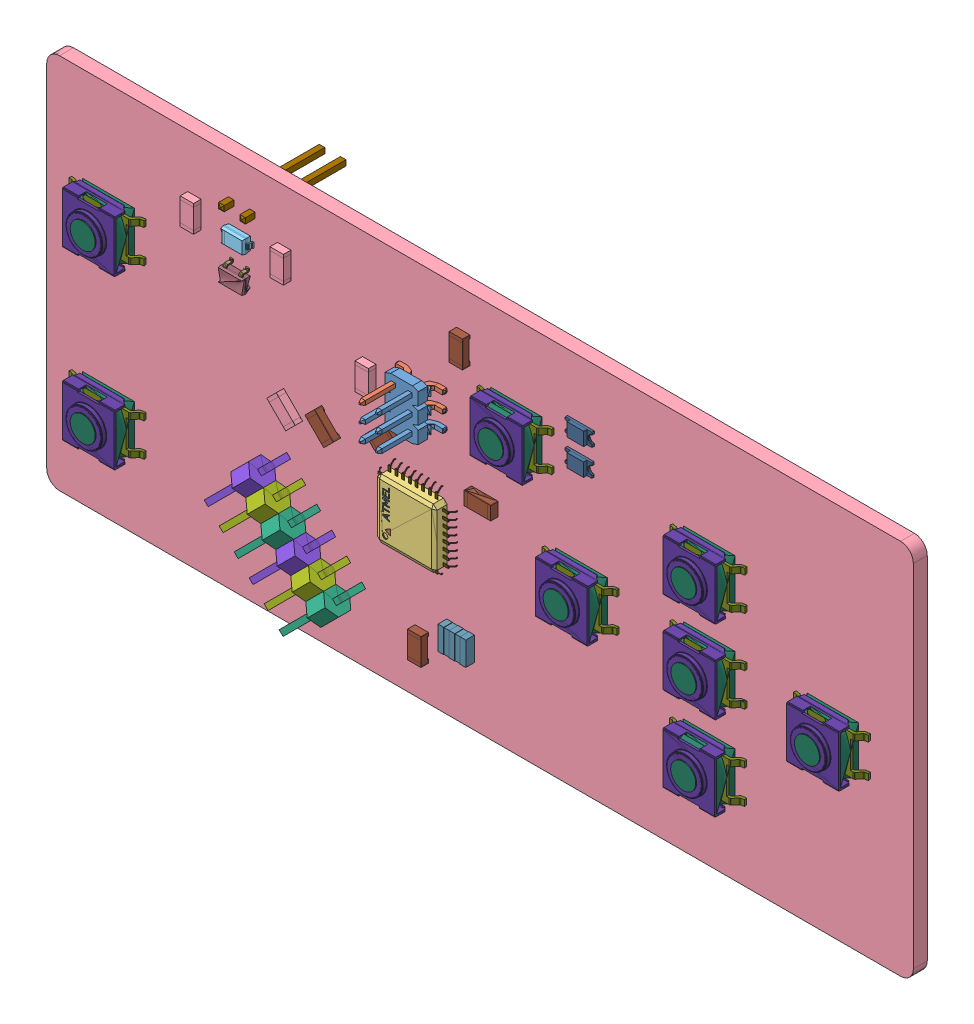
SolidWorks assembly model3, configuration Default. Lengths in mm.
Overall size (103.07 45.07 17.73).
109 component instances, 25 part files, 0 mates.
Components (placement in the parent):
- 2X03SMD-1: 2X03SMD [Default] at (2993.2271 13531.488 -10410.0341) x (-1 0 0) z (0 0 1) size (5.95 6.45 6.6)
  - skpxI6tRR-1: skpxI6tRR [Default] x (0 -1 0) z (0 0 1) size (5.95 5.95 6.6)
    - skpxI6tRR-1-1: skpxI6tRR-1 [Default] at origin size (5.95 4.96 6.6)
    - skpxI6tRR-2-1: skpxI6tRR-2 [Default] at origin size (2.53 5.95 6.6)
    - skpxI6tRR-3-1: skpxI6tRR-3 [Default] at origin size (0.5 2.23 1.49)
  - skpxI6tRR-2: skpxI6tRR [Default] x (0 -1 0) z (0 0 1) size (6.45 5.95 6.55)
- C1206-1: C1206 [Default] at (2986.7985 13530.1039 -10412.8609) x (0 -1 0) z (0 0 1) size (3.18 1.59 0.89)
- C1206-2: C1206 [Default] at (2977.1959 13522.0391 -10412.8609) x (-0.707107 0.707107 0) z (0 0 1) size (3.18 1.59 0.89)
- C1206-3: C1206 [Default] at (2976.6918 13536.8083 -10412.8609) x (0 1 0) z (0 0 1) size (3.18 1.59 0.89)
- C1206-4: C1206 [Default] at (2966.0066 13536.7071 -10412.8609) x (0 -1 0) z (0 0 1) size (3.18 1.59 0.89)
- SOD123-1: SOD123 [Default] at (2971.3993 13536.7071 -10412.8113) size (3.39 1.59 0.99)
- 1X06SMD-1: 1X06SMD [Default] at (2977.8455 13508.7982 -10412.2713) x (-0.707107 -0.707107 0) z (0 0 1) size (10.7 15.51 4.98)
  - PIN_HEADER_L-ANGLE-1: PIN_HEADER_L-ANGLE [Default] at (0 3.7803 0) x (0 0 -1) z (1 0 0) size (4.98 7.95 10.7)
    - Group_28-1: Group_28 [Default] at (0.0033 2.5199 0) size (4.97 2.91 10.7)
    - Group_25-1: Group_25 [Default] at origin size (4.97 2.91 10.7)
    - Group_29-1: Group_29 [Default] at (-0.0033 -2.5199 0) size (4.97 2.91 10.7)
  - PIN_HEADER_L-ANGLE-2: PIN_HEADER_L-ANGLE [Default] at (0 -3.7803 0) x (0 0 -1) z (1 0 0) size (4.98 7.95 10.7)
    - Group_28-1: Group_28 [Default] at (0.0033 2.5199 0) size (4.97 2.91 10.7)
    - Group_25-1: Group_25 [Default] at origin size (4.97 2.91 10.7)
    - Group_29-1: Group_29 [Default] at (-0.0033 -2.5199 0) size (4.97 2.91 10.7)
- 1X2-1: 1X2 [Default] at (2971.5868 13539.7476 -10418.2528) x (1 0 0) z (0 0 -1) size (5.25 2.82 12.38)
  - Componente_1-1: Componente_1 [Default] at origin size (5.25 2.82 12.38)
    - Pin-1: Pin [Default] at (1.2601 0 0) x (0 1 0) z (0 0 1) size (2.82 2.73 12.38)
    - Pin-2: Pin [Default] at (-1.2601 0 0) x (0 1 0) z (0 0 1) size (2.82 2.73 12.38)
- LED_1206-1: LED_1206 [Default] at (3011.9764 13533.8473 -10412.97) x (-1 0 0) z (0 0 1) size (3.18 1.59 0.67)
- LED_1206-2: LED_1206 [Default] at (3011.9818 13537.0252 -10412.97) size (3.18 1.59 0.67)
- R1206-1: R1206 [Default] at (3000.5586 13524.0553 -10412.8609) size (3.18 1.59 0.89)
- R1206-2: R1206 [Default] at (2997.9878 13538.7233 -10412.8609) x (0 1 0) z (0 0 1) size (3.18 1.59 0.89)
- R1206-3: R1206 [Default] at (2988.8901 13525.3154 -10412.8609) x (-0.707107 -0.707107 0) z (0 0 1) size (3.18 1.59 0.89)
- R1206-4: R1206 [Default] at (2993.0485 13505.608 -10412.8609) x (0 1 0) z (0 0 1) size (3.18 1.59 0.89)
- R1206-5: R1206 [Default] at (2981.7323 13522.569 -10412.8609) x (-0.707107 0.707107 0) z (0 0 1) size (3.18 1.59 0.89)
- SOT23-1: SOT23 [Default] at (2971.4251 13532.7253 -10412.7121) x (-1 0 0) z (0 0 1) size (2.88 2.68 1.19)
  - Groupe_1-1: Groupe_1 [Default] at (-0.9426 -1.0666 -0.1488) size (0.66 0.55 0.89)
  - Groupe_1-2: Groupe_1 [Default] at (0.9426 -1.0666 -0.1488) size (0.66 0.55 0.89)
  - Groupe_1-3: Groupe_1 [Default] at (0 1.0666 -0.1488) x (-1 0 0) z (0 0 1) size (0.66 0.55 0.89)
  - SOT23-1: SOT23 [Default] at origin size (2.88 1.59 1.19)
- EFOBM-1: EFOBM [Default] at (2998.2004 13508.7789 -10412.2645) x (0 -1 0) z (0 0 1) size (2.83 3.3 1.04)
- 6MM_SWITCH-1: 6MM_SWITCH [Default] at (3004.2884 13533.3306 -10411.8044) x (-1 0 0) z (0 0 1) size (8.92 6.58 3.14)
  - _1-1: _1 [Default] at (0 0 0.0343) size (6.15 6.15 3.07)
  - _2-1: _2 [Default] at (0 0 -1.0585) size (8.92 4.66 1.03)
  - _3-1: _3 [Default] at (0 0 0.3116) size (6.16 6.58 2.49)
- 6MM_SWITCH-2: 6MM_SWITCH [Default] at (2955.7997 13510.6733 -10411.8044) size (8.92 6.58 3.14)
  - _1-1: _1 [Default] at (0 0 0.0343) size (6.15 6.15 3.07)
  - _2-1: _2 [Default] at (0 0 -1.0585) size (8.92 4.66 1.03)
  - _3-1: _3 [Default] at (0 0 0.3116) size (6.16 6.58 2.49)
- 6MM_SWITCH-3: 6MM_SWITCH [Default] at (3027.2225 13510.6227 -10411.8044) x (-1 0 0) z (0 0 1) size (8.92 6.58 3.14)
  - _1-1: _1 [Default] at (0 0 0.0343) size (6.15 6.15 3.07)
  - _2-1: _2 [Default] at (0 0 -1.0585) size (8.92 4.66 1.03)
  - _3-1: _3 [Default] at (0 0 0.3116) size (6.16 6.58 2.49)
- 6MM_SWITCH-4: 6MM_SWITCH [Default] at (3012.0505 13520.653 -10411.8044) size (8.92 6.58 3.14)
  - _1-1: _1 [Default] at (0 0 0.0343) size (6.15 6.15 3.07)
  - _2-1: _2 [Default] at (0 0 -1.0585) size (8.92 4.66 1.03)
  - _3-1: _3 [Default] at (0 0 0.3116) size (6.16 6.58 2.49)
- 6MM_SWITCH-5: 6MM_SWITCH [Default] at (3027.2483 13520.653 -10411.8044) size (8.92 6.58 3.14)
  - _1-1: _1 [Default] at (0 0 0.0343) size (6.15 6.15 3.07)
  - _2-1: _2 [Default] at (0 0 -1.0585) size (8.92 4.66 1.03)
  - _3-1: _3 [Default] at (0 0 0.3116) size (6.16 6.58 2.49)
- 6MM_SWITCH-6: 6MM_SWITCH [Default] at (2955.7997 13530.5831 -10411.8044) size (8.92 6.58 3.14)
  - _1-1: _1 [Default] at (0 0 0.0343) size (6.15 6.15 3.07)
  - _2-1: _2 [Default] at (0 0 -1.0585) size (8.92 4.66 1.03)
  - _3-1: _3 [Default] at (0 0 0.3116) size (6.16 6.58 2.49)
- 6MM_SWITCH-7: 6MM_SWITCH [Default] at (3041.941 13520.653 -10411.8044) size (8.92 6.58 3.14)
  - _1-1: _1 [Default] at (0 0 0.0343) size (6.15 6.15 3.07)
  - _2-1: _2 [Default] at (0 0 -1.0585) size (8.92 4.66 1.03)
  - _3-1: _3 [Default] at (0 0 0.3116) size (6.16 6.58 2.49)
- 6MM_SWITCH-8: 6MM_SWITCH [Default] at (3027.2483 13530.5077 -10411.8044) size (8.92 6.58 3.14)
  - _1-1: _1 [Default] at (0 0 0.0343) size (6.15 6.15 3.07)
  - _2-1: _2 [Default] at (0 0 -1.0585) size (8.92 4.66 1.03)
  - _3-1: _3 [Default] at (0 0 0.3116) size (6.16 6.58 2.49)
- QFP80P900X900X120-32N-1: QFP80P900X900X120-32N [Default] at (2992.769 13518.6362 -10412.4777) x (0 1 0) z (0 0 1) size (9.13 9.12 1.66)
  - Pin_microcontoller-1: Pin_microcontoller [Default] at (-2.8113 -4.0273 -0.452) x (0.999946 -0.010347 0) z (0 0 1) size (0.3 1.03 0.73)
  - Pin_microcontoller-2: Pin_microcontoller [Default] at (-2.0034 -4.0303 -0.455) x (0.999946 -0.010347 0) z (0 0 1) size (0.3 1.03 0.73)
  - Pin_microcontoller-3: Pin_microcontoller [Default] at (-1.2066 -4.0418 -0.4449) x (0.999946 -0.010347 0) z (0 0 1) size (0.3 1.03 0.73)
  - Pin_microcontoller-4: Pin_microcontoller [Default] at (-0.3987 -4.0447 -0.4479) x (0.999946 -0.010347 0) z (0 0 1) size (0.3 1.03 0.73)
  - Pin_microcontoller-5: Pin_microcontoller [Default] at (1.9774 -4.0152 -0.4378) x (0.999946 -0.010347 0) z (0 0 1) size (0.3 1.03 0.73)
  - Pin_microcontoller-6: Pin_microcontoller [Default] at (0.3728 -4.0007 -0.4449) x (0.999946 -0.010347 0) z (0 0 1) size (0.3 1.03 0.73)
  - Pin_microcontoller-7: Pin_microcontoller [Default] at (2.7853 -4.0181 -0.4408) x (0.999946 -0.010347 0) z (0 0 1) size (0.3 1.03 0.73)
  - Pin_microcontoller-8: Pin_microcontoller [Default] at (1.1807 -4.0036 -0.4479) x (0.999946 -0.010347 0) z (0 0 1) size (0.3 1.03 0.73)
  - Pin_microcontoller-9: Pin_microcontoller [Default] at (1.1678 4.0418 -0.4458) x (-0.999946 0.010347 0) z (0 0 1) size (0.3 1.03 0.73)
  - Pin_microcontoller-10: Pin_microcontoller [Default] at (0.3599 4.0447 -0.4489) x (-0.999946 0.010347 0) z (0 0 1) size (0.3 1.03 0.73)
  - Pin_microcontoller-11: Pin_microcontoller [Default] at (1.9645 4.0303 -0.4559) x (-0.999946 0.010347 0) z (0 0 1) size (0.3 1.03 0.73)
  - Pin_microcontoller-12: Pin_microcontoller [Default] at (-2.0162 4.0152 -0.4388) x (-0.999946 0.010347 0) z (0 0 1) size (0.3 1.03 0.73)
  - Pin_microcontoller-13: Pin_microcontoller [Default] at (-0.4116 4.0007 -0.4458) x (-0.999946 0.010347 0) z (0 0 1) size (0.3 1.03 0.73)
  - Pin_microcontoller-14: Pin_microcontoller [Default] at (-2.8241 4.0181 -0.4418) x (-0.999946 0.010347 0) z (0 0 1) size (0.3 1.03 0.73)
  - Pin_microcontoller-15: Pin_microcontoller [Default] at (-1.2195 4.0036 -0.4489) x (-0.999946 0.010347 0) z (0 0 1) size (0.3 1.03 0.73)
  - Pin_microcontoller-16: Pin_microcontoller [Default] at (2.7724 4.0273 -0.4529) x (-0.999946 0.010347 0) z (0 0 1) size (0.3 1.03 0.73)
  - Pin_microcontoller-17: Pin_microcontoller [Default] at (-4.0031 -0.3628 -0.4556) x (-0.010347 -0.999946 0) z (0 0 1) size (0.3 1.03 0.73)
  - Pin_microcontoller-18: Pin_microcontoller [Default] at (-4.0297 2.8212 -0.4627) x (-0.010347 -0.999946 0) z (0 0 1) size (0.3 1.03 0.73)
  - Pin_microcontoller-19: Pin_microcontoller [Default] at (-4.0442 1.2166 -0.4556) x (-0.010347 -0.999946 0) z (0 0 1) size (0.3 1.03 0.73)
  - Pin_microcontoller-20: Pin_microcontoller [Default] at (-4.0471 0.4087 -0.4587) x (-0.010347 -0.999946 0) z (0 0 1) size (0.3 1.03 0.73)
  - Pin_microcontoller-21: Pin_microcontoller [Default] at (-4.0326 2.0133 -0.4657) x (-0.010347 -0.999946 0) z (0 0 1) size (0.3 1.03 0.73)
  - Pin_microcontoller-22: Pin_microcontoller [Default] at (-4.0176 -1.9675 -0.4486) x (-0.010347 -0.999946 0) z (0 0 1) size (0.3 1.03 0.73)
  - Pin_microcontoller-23: Pin_microcontoller [Default] at (-4.0205 -2.7754 -0.4516) x (-0.010347 -0.999946 0) z (0 0 1) size (0.3 1.03 0.73)
  - Pin_microcontoller-24: Pin_microcontoller [Default] at (-4.006 -1.1707 -0.4587) x (-0.010347 -0.999946 0) z (0 0 1) size (0.3 1.03 0.73)
  - Pin_microcontoller-25: Pin_microcontoller [Default] at (4.0326 -1.9751 -0.4479) x (0.010347 0.999946 0) z (0 0 1) size (0.3 1.03 0.73)
  - Pin_microcontoller-26: Pin_microcontoller [Default] at (4.0297 -2.783 -0.4449) x (0.010347 0.999946 0) z (0 0 1) size (0.3 1.03 0.73)
  - Pin_microcontoller-27: Pin_microcontoller [Default] at (4.0031 0.401 -0.4378) x (0.010347 0.999946 0) z (0 0 1) size (0.3 1.03 0.73)
  - Pin_microcontoller-28: Pin_microcontoller [Default] at (4.0442 -1.1784 -0.4378) x (0.010347 0.999946 0) z (0 0 1) size (0.3 1.03 0.73)
  - Pin_microcontoller-29: Pin_microcontoller [Default] at (4.0471 -0.3705 -0.4408) x (0.010347 0.999946 0) z (0 0 1) size (0.3 1.03 0.73)
  - Pin_microcontoller-30: Pin_microcontoller [Default] at (4.0176 2.0057 -0.4307) x (0.010347 0.999946 0) z (0 0 1) size (0.3 1.03 0.73)
  - Pin_microcontoller-31: Pin_microcontoller [Default] at (4.0205 2.8136 -0.4338) x (0.010347 0.999946 0) z (0 0 1) size (0.3 1.03 0.73)
  - Pin_microcontoller-32: Pin_microcontoller [Default] at (4.006 1.2089 -0.4408) x (0.010347 0.999946 0) z (0 0 1) size (0.3 1.03 0.73)
  - ATMEL-1: ATMEL [Default] at (0.9788 2.3333 0.8105) size (3.47 0.76 0.04)
    - ATMEL-1-1: ATMEL-1 [Default] at origin size (3.47 0.76 0.04)
  - ATMEL-2: ATMEL [Default] at (0.9788 2.3333 0.8105) size (3.47 0.76 0.04)
  - _-1: _ [Default] at (-1.7862 2.132 0.7865) size (0.76 0.66 0.05)
  - QFP80P900X900X120-32N-1: QFP80P900X900X120-32N [Default] at origin size (7.08 7.08 1.6)
- model3-1: model3 [Default] at origin size (102.89 44.44 1.59) (hidden)
- Part30^model3-1: Part30^model3 [Default] at (0 0 -10413.365) size (103.07 44.81 1.65) (virtual)
